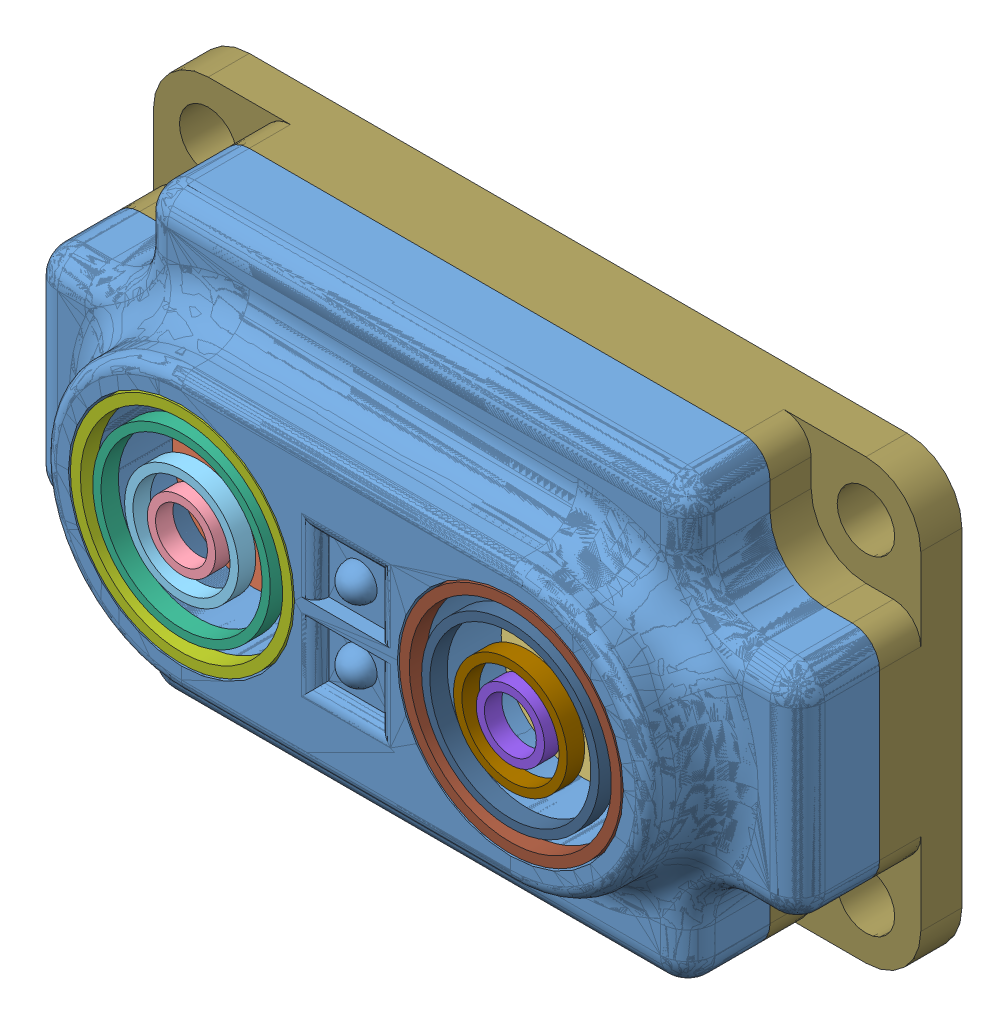
SolidWorks assembly 45-2008_Range, configuration Default. Lengths in mm.
Overall size (56.42 32.42 17.23).
13 component instances, 12 part files, 0 mates.
Components (placement in the parent):
- 45-0216-1: 45-0216 [Default] at (1.312 8.315 5.4729) size (56.42 32.42 11.23)
- Part 2-1: Part 2 [Default] at (1.312 8.315 5.4729) size (12.06 12.06 5.59)
- Part 3-1: Part 3 [Default] at (1.312 8.315 5.4729) size (12.06 12.06 5.59)
- Part 4-1: Part 4 [Default] at (1.312 8.315 5.4729) size (4.98 4.98 1.27)
- Part 5-1: Part 5 [Default] at (1.312 8.315 5.4729) size (8.3 8.3 1.27)
- Part 6-1: Part 6 [Default] at (1.312 8.315 5.4729) size (12.95 12.95 1.27)
- Part 7-1: Part 7 [Default] at (1.312 8.315 5.4729) size (16.21 16.21 1.27)
- Part 8-1: Part 8 [Default] at (1.312 8.315 5.4729) size (4.98 4.98 1.27)
- Part 9-1: Part 9 [Default] at (1.312 8.315 5.4729) size (8.3 8.3 1.27)
- Part 10-1: Part 10 [Default] at (1.312 8.315 5.4729) size (12.95 12.95 1.27)
- Part 11-1: Part 11 [Default] at (1.312 8.315 5.4729) size (16.21 16.21 1.27)
- 45-0201-1: 45-0201 [Default] at (1.312 8.315 -0.5271) size (56 32 6)
- 45-0216-2: 45-0216 [Default] at (57.312 40.315 5.4729) x (-1 0 0) z (0 0 1) size (56.42 32.42 11.23)
